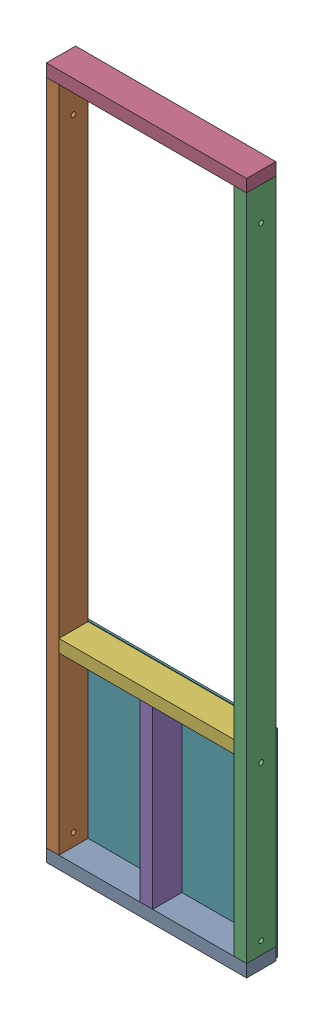
SolidWorks assembly short pannel, configuration Default. Lengths in mm.
Overall size (609.6 2108.2 94.46).
7 component instances, 4 part files, 23 mates.
Components (placement in the parent):
- 2x4x24-1: 2x4x24 [Default] x (0 0 -1) z (0 1 0) size (88.9 609.6 38.1)
- 2x4x80-Hole-1: 2x4x80-Hole [Default] at (-590.55 19.05 0) x (0 0 1) z (-1 0 0) size (88.9 2032 38.1)
- 2x4x80-Hole-2: 2x4x80-Hole [Default] at (-19.05 19.05 0) x (0 0 1) z (-1 0 0) size (88.9 2032 38.1)
- 2x4x24-2: 2x4x24 [Default] at (0 2070.1 0) x (0 0 -1) z (0 1 0) size (88.9 609.6 38.1)
- 2x4x21-2: 2x4x21 [Default] at (-304.8 19.05 0) x (0 0 -1) z (1 0 0) size (88.9 533.4 38.1)
- 2x4x21-3: 2x4x21 [Default] at (-38.1 571.5 0) x (0 0 -1) z (0 1 0) size (88.9 533.4 38.1)
- plywoodx24x23.7 plywood-1: plywoodx24x23.7 plywood [Default] at (-304.8 290.5125 -44.45) x (1 0 0) z (0 1 0) size (609.6 5.56 603.88)
Mates (geometry in assembly coordinates):
- Coincident1: coincident anti-aligned: plane of 2x4x24-1 through (-609.6 19.05 44.45) normal (0 1 0); plane of 2x4x80-Hole-1 through (-590.55 19.05 0) normal (0 -1 0)
- Coincident2: coincident aligned: plane of 2x4x24-1 through (-609.6 0 0) normal (-1 0 0); plane of 2x4x80-Hole-1 through (-609.6 2051.05 -44.45) normal (-1 0 0)
- Coincident3: coincident aligned: plane of 2x4x24-1 through (-609.6 19.05 44.45) normal (0 0 1); plane of 2x4x80-Hole-1 through (-609.6 2051.05 44.45) normal (0 0 1)
- Coincident4: coincident anti-aligned: plane of 2x4x24-1 through (-609.6 19.05 44.45) normal (0 1 0); plane of 2x4x80-Hole-2 through (-19.05 19.05 0) normal (0 -1 0)
- Coincident5: coincident aligned: plane of 2x4x24-1 through (-609.6 19.05 44.45) normal (0 0 1); plane of 2x4x80-Hole-2 through (-38.1 2051.05 44.45) normal (0 0 1)
- Coincident6: coincident aligned: plane of 2x4x24-1 through (0 0 0) normal (1 0 0); plane of 2x4x80-Hole-2 through (0 2051.05 -44.45) normal (1 0 0)
- Coincident7: coincident anti-aligned: plane of 2x4x80-Hole-1 through (-590.55 2051.05 0) normal (0 1 0); plane of 2x4x24-2 through (-609.6 2051.05 44.45) normal (0 -1 0)
- Coincident8: coincident aligned: plane of 2x4x80-Hole-1 through (-609.6 2051.05 44.45) normal (0 0 1); plane of 2x4x24-2 through (-609.6 2089.15 44.45) normal (0 0 1)
- Coincident9: coincident aligned: plane of 2x4x80-Hole-2 through (0 2051.05 -44.45) normal (1 0 0); plane of 2x4x24-2 through (0 2070.1 0) normal (1 0 0)
- Coincident10: coincident: plane of 2x4x80-Hole-1 through (-571.5 2051.05 -44.45) normal (1 0 0); plane of 2x4x21-1 through (-571.5 854.0046 0) normal (-1 0 0)
- Coincident11: coincident aligned: plane of 2x4x80-Hole-1 through (-609.6 2051.05 44.45) normal (0 0 1); plane of 2x4x21-1 through (-38.1 834.9546 44.45) normal (0 0 1)
- Coincident12: coincident anti-aligned: plane of 2x4x24-1 through (-609.6 19.05 44.45) normal (0 1 0); plane of 2x4x21-2 through (-304.8 19.05 0) normal (0 -1 0)
- Coincident13: coincident aligned: plane of 2x4x24-1 through (-609.6 19.05 44.45) normal (0 0 1); plane of 2x4x21-2 through (-285.75 552.45 44.45) normal (0 0 1)
- Symmetric1: symmetric aligned: plane of 2x4x80-Hole-1 through (-571.5 2051.05 -44.45) normal (1 0 0); plane of 2x4x21-2 through (-38.1 2051.05 -44.45) normal (-1 0 0); plane of 2x4x80-Hole-2 through (-304.8 19.05 0) normal (1 0 0)
- Coincident14: coincident anti-aligned: plane of 2x4x21-2 through (-304.8 552.45 0) normal (0 1 0); plane of 2x4x21-3 through (-571.5 552.45 44.45) normal (0 -1 0)
- Coincident15: coincident aligned: plane of 2x4x21-2 through (-285.75 552.45 44.45) normal (0 0 1); plane of 2x4x21-3 through (-571.5 590.55 44.45) normal (0 0 1)
- Coincident16: coincident anti-aligned: plane of 2x4x80-Hole-1 through (-571.5 2051.05 -44.45) normal (1 0 0); plane of 2x4x21-3 through (-571.5 571.5 0) normal (-1 0 0)
- Coincident17: coincident anti-aligned: plane of 2x4x80-Hole-1 through (-609.6 2051.05 -44.45) normal (0 0 -1); plane of plywoodx24x23.775 plywood-1 through (0 289.56 -44.45) normal (0 0 1)
- Coincident18: coincident aligned: plane of 2x4x80-Hole-1 through (-609.6 2051.05 -44.45) normal (-1 0 0); plane of plywoodx24x23.775 plywood-1 through (-609.6 -11.43 -44.45) normal (-1 0 0)
- Coincident19: coincident aligned: plane of 2x4x21-3 through (-571.5 590.55 44.45) normal (0 1 0); plane of plywoodx24x23.775 plywood-1 through (-609.6 590.55 -44.45) normal (0 1 0)
- Coincident20: coincident anti-aligned: plane of 2x4x80-Hole-1 through (-609.6 2051.05 -44.45) normal (0 0 -1); plane of plywoodx24x23.7 plywood-1 through (-304.8 290.5125 -44.45) normal (0 0 1)
- Coincident21: coincident aligned: plane of 2x4x80-Hole-1 through (-609.6 2051.05 -44.45) normal (-1 0 0); plane of plywoodx24x23.7 plywood-1 through (-609.6 592.455 -50.0063) normal (-1 0 0)
- Distance1: distance = 7.62 mm aligned: plane of 2x4x24-1 through (-609.6 -19.05 44.45) normal (0 -1 0); plane of plywoodx24x23.7 plywood-1 through (-609.6 -11.43 -50.0063) normal (0 -1 0)
